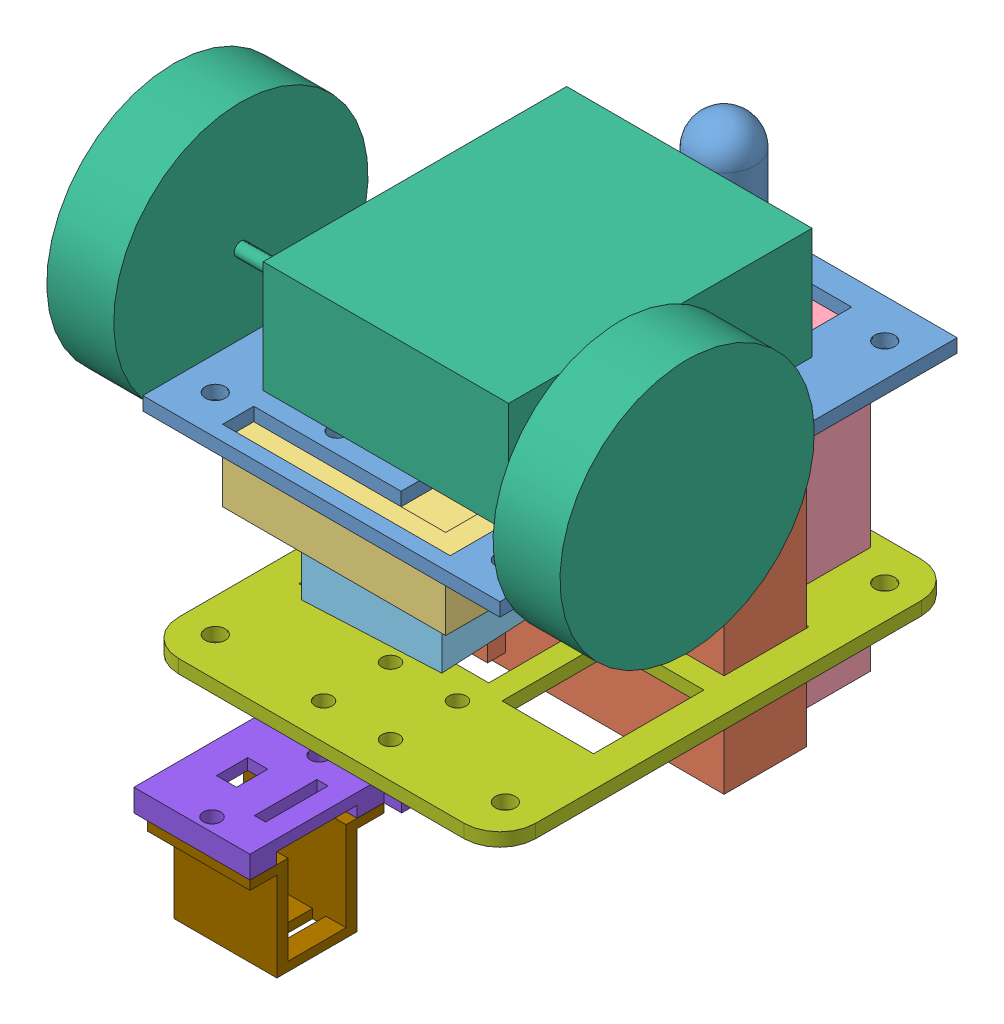
SolidWorks assembly assemblé, configuration Défaut. Lengths in mm.
Overall size (115 120.5 129.47).
9 component instances, 9 part files, 28 mates.
Components (placement in the parent):
- socle-1: socle [Défaut] at (-48.0685 -7.0695 3.2312) size (80 33 102.47)
- batteries gros-1: batteries gros [Défaut] at (-47.5685 -40.5695 -3.2688) x (1 0 0) z (0 0 -1) size (64 67 22.5)
- cerveau-1: cerveau [Défaut] at (-48.5685 -13.5695 26.0985) x (1 0 0) z (0 -1 0) size (50 50 13)
- batteries petit-2: batteries petit [Défaut] at (-48.0685 -41.0695 -44.6362) x (-1 0 0) z (0 0 1) size (48 68 20.5)
- pont H-2: pont H [Défaut] at (-48.5685 -36.0695 26.0985) x (-0.050033 0 -0.998748) z (0 1 0) size (35 30 14)
- moteur + roues-1: moteur + roues [Défaut] at (-48.0685 -4.0695 6.003) x (1 0 0) z (0 1 0) size (115 86.5 57)
- milieu-1: milieu [Défaut] at (-48.0685 -54.0695 3.2312) size (80 3 102.47)
- support servo-1: support servo [Défaut] at (-33.0685 -54.0695 86.4659) x (-1 0 0) z (0 0 1) size (30 5 55)
- fix servo-1: fix servo [Défaut] at (-37.0341 -59.0695 81.4659) x (-1 0 0) z (0 0 1) size (23 22 30)
Mates (geometry in assembly coordinates):
- Coïncidente1: coincident anti-aligned: plane of socle-1 through (-48.0685 -7.0695 3.2312) normal (0 -1 0); plane of batteries gros-1 through (-15.5685 -7.0695 -21.7688) normal (0 1 0)
- Parallèle1: parallel anti-aligned: plane of socle-1 through (-88.0685 -7.0695 -96.7688) normal (-1 0 0); plane of batteries gros-1 through (-15.5685 -7.0695 -21.7688) normal (1 0 0)
- Coïncidente5: coincident anti-aligned: plane of socle-1 through (-48.0685 -7.0695 3.2312) normal (0 -1 0); plane of batteries petit-2 through (-72.0685 -7.0695 -26.1362) normal (0 1 0)
- Parallèle2: parallel aligned: plane of socle-1 through (-48.0685 2.9305 -48.0036) normal (0 0 -1); plane of batteries petit-2 through (-48.0685 -41.0695 -44.6362) normal (0 0 -1)
- Coïncidente7: coincident aligned: line of socle-1 through (-72.0685 -7.0695 -25.6362) axis (0 0 -1); line of batteries petit-2 through (-72.0685 -7.0695 -26.1362) axis (0 0 -1)
- Coïncidente8: coincident anti-aligned: line of socle-1 through (-72.0685 -7.0695 -44.6362) axis (1 0 0); line of batteries petit-2 through (-24.0685 -7.0695 -44.6362) axis (-1 0 0)
- Coïncidente9: coincident anti-aligned: plane of socle-1 through (-48.0685 -7.0695 3.2312) normal (0 -1 0); plane of cerveau-1 through (-48.5685 -7.0695 26.0985) normal (0 1 0)
- Coïncidente10: coincident: line of socle-1 through (-73.5685 -7.0695 51.0985) axis (1 0 0); plane of cerveau-1 through (-73.5685 -7.0695 51.0985) normal (0 0 1)
- Coïncidente11: coincident: line of socle-1 through (-73.5685 -7.0695 51.0985) axis (0 0 -1); plane of cerveau-1 through (-73.5685 -7.0695 1.0985) normal (-1 0 0)
- Parallèle4: parallel anti-aligned: plane of cerveau-1 through (-48.5685 -20.0695 26.0985) normal (0 -1 0); plane of pont H-2 through (-48.5685 -22.0695 26.0985) normal (0 1 0)
- Coaxiale3: concentric anti-aligned: circle of cerveau-1; circle of pont H-2
- Coaxiale4: concentric anti-aligned: circle of cerveau-1; circle of pont H-2
- Distance1: distance = 2 mm anti-aligned: plane of pont H-2 through (-48.5685 -22.0695 26.0985) normal (0 1 0); plane of cerveau-1 through (-48.5685 -20.0695 26.0985) normal (0 -1 0)
- Coïncidente21: coincident aligned: line of socle-1 through (-80.5685 -7.0695 -3.2688) axis (1 0 0); line of batteries gros-1 through (-79.5685 -7.0695 -3.2688) axis (1 0 0)
- Coïncidente22: coincident: line of socle-1 through (-15.5685 -7.0695 -3.2688) axis (0 0 -1); plane of batteries gros-1 through (-15.5685 -7.0695 -21.7688) normal (1 0 0)
- Coïncidente23: coincident anti-aligned: plane of socle-1 through (-48.0685 -4.0695 3.2312) normal (0 1 0); plane of moteur + roues-1 through (-48.0685 -4.0695 6.003) normal (0 -1 0)
- Coaxiale5: concentric anti-aligned: circle of moteur + roues-1; circle of socle-1
- Parallèle5: parallel aligned: plane of socle-1 through (-8.0685 -7.0695 -96.7688) normal (1 0 0); plane of moteur + roues-1 through (-20.5685 20.9305 40.003) normal (1 0 0)
- Parallèle6: parallel anti-aligned: plane of socle-1 through (-48.0685 -7.0695 3.2312) normal (0 -1 0); plane of milieu-1 through (-48.0685 -51.0695 3.2312) normal (0 1 0)
- Coaxiale6: concentric aligned: circle of socle-1; circle of milieu-1
- Coaxiale7: concentric aligned: circle of socle-1; circle of milieu-1
- Distance2: distance = 15 mm anti-aligned: plane of milieu-1 through (-48.0685 -51.0695 3.2312) normal (0 1 0); plane of pont H-2 through (-48.5685 -36.0695 26.0985) normal (0 -1 0)
- Coïncidente25: coincident anti-aligned: plane of milieu-1 through (-48.0685 -54.0695 3.2312) normal (0 -1 0); plane of support servo-1 through (-33.0685 -54.0695 86.4659) normal (0 1 0)
- Coaxiale9: concentric anti-aligned: circle of milieu-1; circle of support servo-1
- Coaxiale10: concentric anti-aligned: circle of milieu-1; circle of support servo-1
- Coïncidente28: coincident anti-aligned: plane of support servo-1 through (-33.0685 -59.0695 86.4659) normal (0 -1 0); plane of fix servo-1 through (-37.0341 -59.0695 81.4659) normal (0 1 0)
- Parallèle8: parallel aligned: line of support servo-1 through (-44.0685 -56.5695 73.4659) axis (0 0 -1); line of fix servo-1 through (-44.5341 -81.0695 72.9659) axis (0 0 -1)
- Coaxiale11: concentric aligned: circle of support servo-1; circle of fix servo-1
